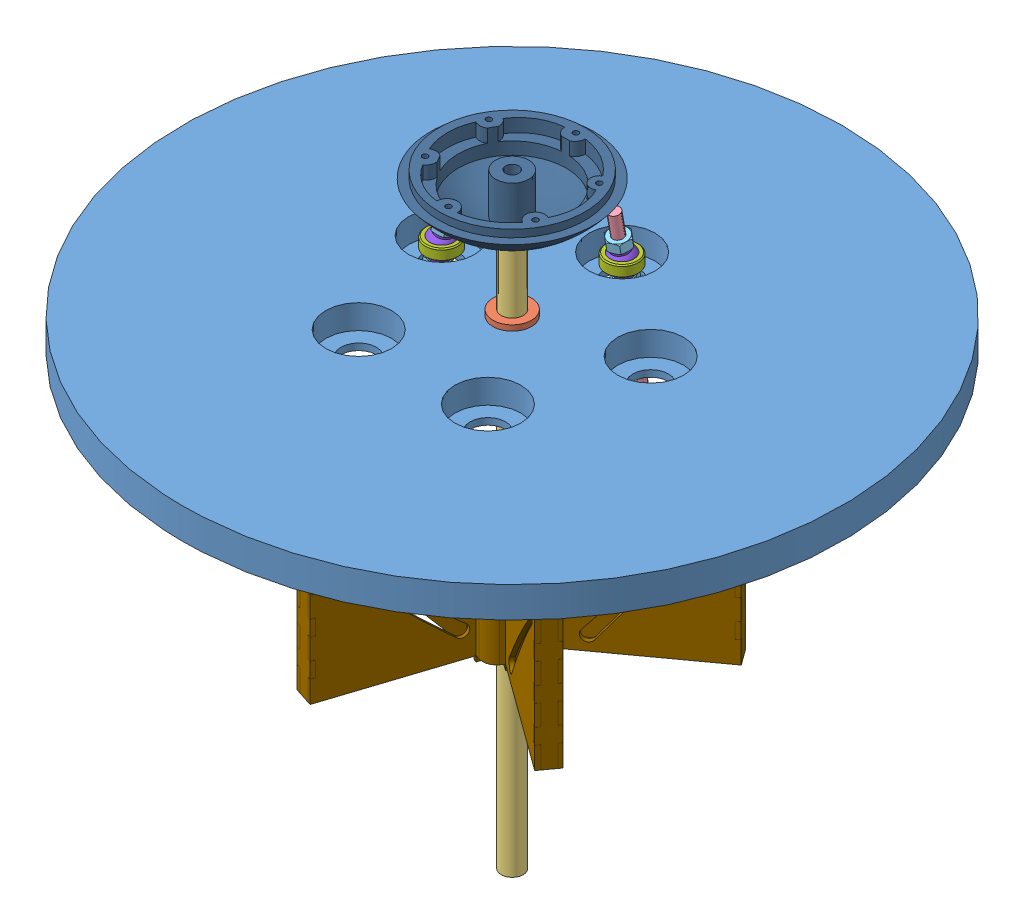
SolidWorks assembly upper_assembly, configuration Default. Lengths in mm.
Overall size (381 349.68 381).
21 component instances, 10 part files, 11 mates.
Components (placement in the parent):
- upper_plate-1: upper_plate [Default] at origin size (381 17.78 381)
- vertical_bushing-1: vertical_bushing [3113K62] at (0 20.955 0) x (-0.837169 0 -0.546944) z (-0.546944 0 0.837169) size (22.23 19.05 22.23)
- vertical_tube-1: vertical_tube [Default] at (0 -233.5188 0) x (-1 0 0) z (0 0 -1) size (12.7 330.2 12.7)
- follower_assem-1: follower_assem [Default] at (0 -51.1375 -74.9813) x (0 0.985062 0.172198) z (0.244227 -0.166984 0.955233) size (131.4 27.36 27.36) (flexible)
  - .25_threaded_rod-1: .25_threaded_rod [90322A653] at origin size (131.2 6.35 6.35)
  - 1_4_20_nut-1: 1_4_20_nut [95462A029] at (56.3658 0 0) x (0 0.212547 0.977151) z (-1 0 0) size (11.11 12.83 7.14)
  - 1_4_20_nut-2: 1_4_20_nut [95462A029] at (76.9842 0 0) x (0 0.092583 -0.995705) z (-1 0 0) size (11.11 12.83 7.14)
  - spring_pin-2: spring_pin [98296A881] at (-34.925 0 0) x (-0.475165 0 0.879897) z (0 1 0) size (4.81 5.08 19.05)
  - swivel_bearing-1: swivel_bearing [Default] at (66.675 0 0) x (0.985062 -0.042056 -0.166984) z (0.140416 0.757502 0.637553) size (17.79 21.8 22.4) (flexible)
    - ball2-1: ball2 [Default] at origin size (6.48 18.8 18.8)
    - ball-1: ball [Default] x (0.985062 -0.099678 0.140416) z (-0.170483 -0.449709 0.876754) size (15.06 15.18 15.18)
- follower_assem-2: follower_assem [Default] at (-72.4602 -50.9767 -16.9246) x (0.181 0.98265 -0.040465) z (-0.949093 0.163737 -0.269095) size (131.5 27.36 27.36) (flexible)
  - .25_threaded_rod-1: .25_threaded_rod [90322A653] at origin size (131.2 6.35 6.35)
  - 1_4_20_nut-1: 1_4_20_nut [95462A029] at (56.3658 0 0) x (0 -0.985979 -0.16687) z (-1 0 0) size (11.11 12.83 7.14)
  - 1_4_20_nut-2: 1_4_20_nut [95462A029] at (76.9842 0 0) x (0 0.889498 0.456939) z (-1 0 0) size (11.11 12.83 7.14)
  - spring_pin-2: spring_pin [98296A881] at (-34.925 0 0) x (0.593789 0 0.80462) z (0 1 0) size (4.81 5.08 19.05)
  - swivel_bearing-1: swivel_bearing [Default] at (66.675 0 0) x (0.98265 -0.087111 0.163737) z (-0.137769 -0.933888 0.32996) size (18.22 22.16 22.43) (flexible)
    - ball2-1: ball2 [Default] at origin size (6.48 18.8 18.8)
    - ball-1: ball [Default] x (0.98265 -0.124169 -0.137769) z (0.179744 0.45445 0.872449) size (15.06 15.18 15.18)
- star2_part-1: star2_part [Default] at (0 -142.4944 0) x (0 0 1) z (-1 0 0) size (185.59 92.08 176.51)
- sphere base-2: sphere base [Default] at (0 123.2489 0) size (93.98 26.86 93.98)
Mates (geometry in assembly coordinates):
- Coincident1: coordinate: point of upper_plate-1; point of assembly
- Concentric6: concentric: cylinder of upper_plate-1 through (0 17.78 0) axis (0 -1 0) radius 7.5692; cylinder of vertical_bushing-1 through (0 1.905 0) axis (0 1 0) radius 7.9629
- Coincident7: coincident: plane of upper_plate-1 through (0 17.78 0) normal (0 1 0); plane of vertical_bushing-1 through (0 17.78 0) normal (0 -1 0)
- Concentric7: concentric: cylinder of vertical_bushing-1 through (0 1.905 0) axis (0 1 0) radius 6.3627; cylinder of vertical_tube-1 through (0 -258.9188 0) axis (0 -1 0) radius 6.35
- Concentric12: concentric: cylinder of upper_plate-1 through (0 17.78 -63.5) axis (0 -1 0) radius 10.2743; cylinder of follower_assem-1/swivel_bearing-1/ball2-1 through (0 7.0104 -63.5) axis (0 -1 0) radius 9.398
- Coincident11: coincident: plane of upper_plate-1 through (0 17.78 0) normal (0 1 0); plane of follower_assem-1/swivel_bearing-1/ball2-1 through (7.6634 17.78 -58.0599) normal (0 1 0)
- Concentric16: concentric: cylinder of upper_plate-1 through (-60.3921 17.78 -19.6226) axis (0 -1 0) radius 10.2743; cylinder of follower_assem-2/swivel_bearing-1/ball2-1 through (-60.3921 7.0104 -19.6226) axis (0 -1 0) radius 9.398
- Coincident16: coincident: plane of upper_plate-1 through (0 17.78 0) normal (0 1 0); plane of follower_assem-2/swivel_bearing-1/ball2-1 through (-52.7287 17.78 -14.1825) normal (0 1 0)
- Concentric17: concentric: cylinder of vertical_tube-1 through (0 -258.9188 0) axis (0 1 0) radius 6.35; cylinder of star2_part-1 through (0 -66.2944 0) axis (0 -1 0) radius 6.604
- Concentric19: concentric: cylinder of vertical_tube-1 through (0 -58.0859 -1.27) axis (0 0 -1) radius 1.5875; cylinder of star2_part-1 through (0 -58.0859 -21.4989) axis (0 0 1) radius 1.5875
- Concentric20: concentric: cylinder of vertical_tube-1 through (0 -258.9188 0) axis (0 1 0) radius 6.35; circle of sphere base-2
